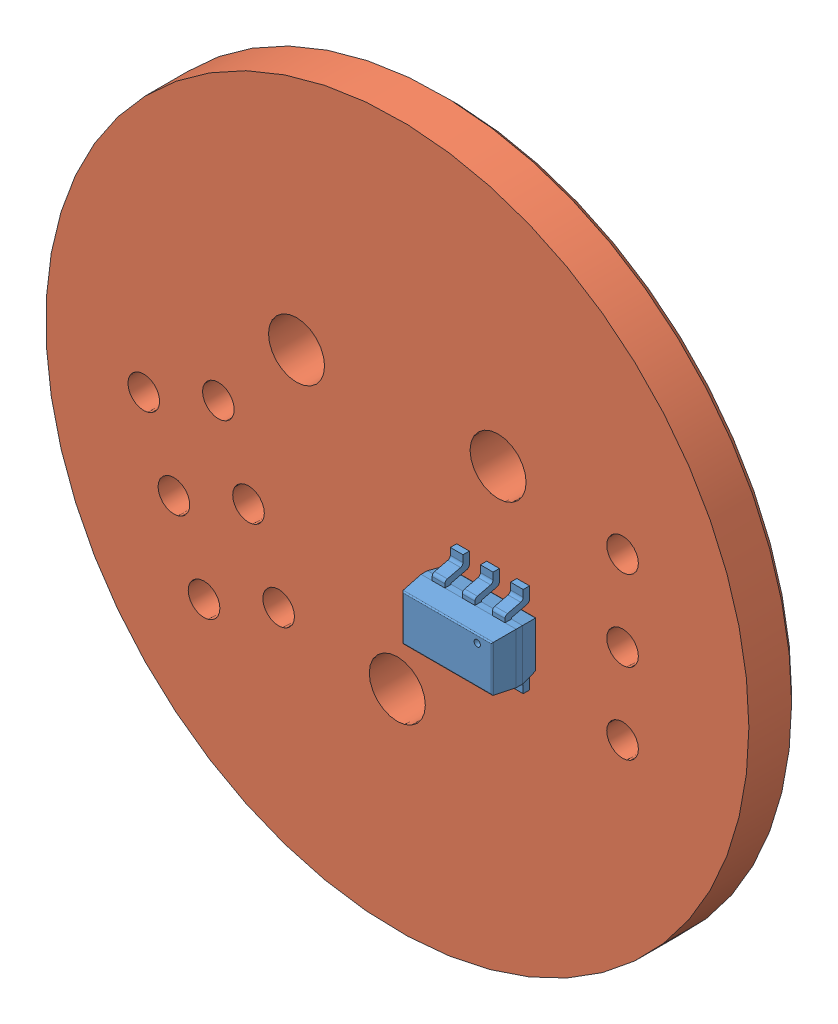
SolidWorks assembly Vishay 357 Pot Amplifier, configuration Default. Lengths in mm.
Overall size (22.2 22.2 3.1).
4 component instances, 2 part files, 0 mates.
Components (placement in the parent):
- Vishay 357 Pot Amplifier.step-1: Vishay 357 Pot Amplifier.step [Default] at origin size (22.2 22.2 3.1)
  - APX321WG-7.step-1: APX321WG-7.step [Default] at (146.05 -104.1146 1.65) x (0 -1 0) z (0 0 1) size (2.85 3 1.45)
    - COMPOUND.step-1: COMPOUND.step [Default] at origin size (2.85 3 1.45)
  - Vishay 357 Pot Amplifier PCB.step-1: Vishay 357 Pot Amplifier PCB.step [Default] at origin size (22.2 22.2 1.6)
